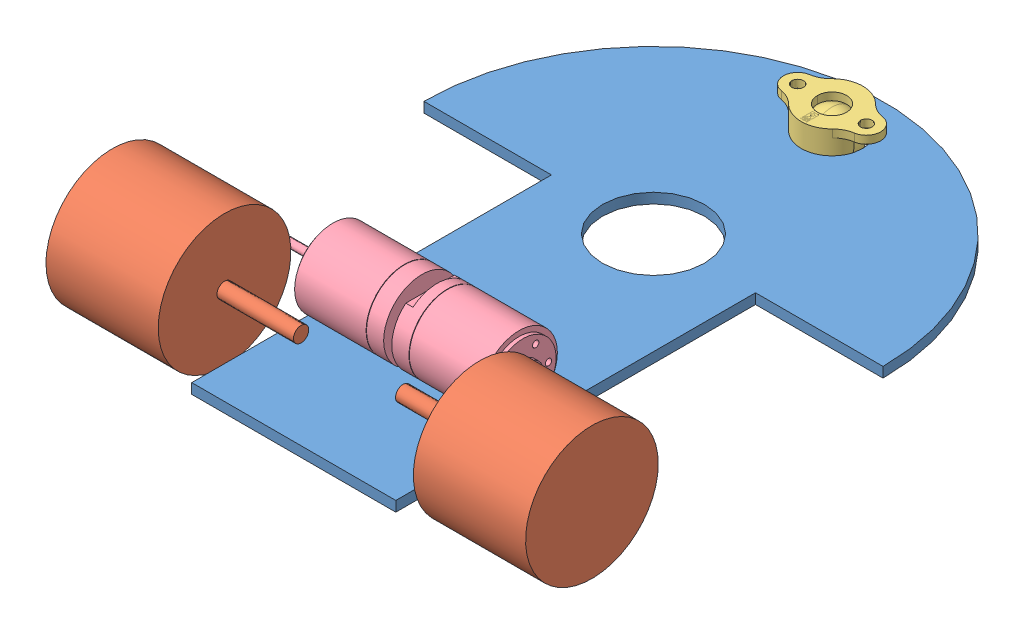
SolidWorks assembly Robot, configuration Défaut. Lengths in mm.
Overall size (94 27.84 117.98).
6 component instances, 4 part files, 13 mates.
Components (placement in the parent):
- PCB-1: PCB [Défaut] at (2.6234 1.4777 105.5) size (90 2 115.5)
- Roue-3: Roue [Défaut] at (22.6234 10.9777 124.0626) x (0 -0.073602 -0.997288) z (1 0 0) size (26 26 37)
- pololu-ball-caster-with-0-375in-ball.step-1: pololu-ball-caster-with-0-375in-ball.step [Défaut] at (-2.3766 6.5227 30) x (-1 0 0) z (0 -1 0) size (19.05 12.07 10.07)
- Moteur+encodeur.stp-2: Moteur+encodeur.stp [Défaut] at (0.8234 10.9777 109.585) x (0 0 1) z (1 0 0) size (15 15 26.3)
- Moteur+encodeur.stp-4: Moteur+encodeur.stp [Défaut] at (-5.5766 10.9777 109.585) x (0 0 1) z (-1 0 0) size (15 15 26.3)
- Roue-11: Roue [Défaut] at (-27.3766 10.9777 124.0626) x (0 0.073602 0.997288) z (-1 0 0) size (26 26 37)
Mates (geometry in assembly coordinates):
- Distance2: distance = 5 mm anti-aligned: plane of Roue-2 through (22.6234 10.9777 80.5) normal (-1 0 0); plane of PCB-1 through (17.6234 3.4777 105.5) normal (1 0 0)
- Distance6: distance = 7.5 mm: plane of PCB-1 through (2.6234 3.4777 105.5) normal (0 1 0); cylinder of Roue-2 through (7.6234 10.9777 80.5) axis (1 0 0) radius 1.5
- Distance3: distance = 2.5 mm anti-aligned: cylinder of Roue-2 through (44.6234 10.9777 80.5) axis (-1 0 0) radius 13; plane of PCB-1 through (2.6234 3.4777 65) normal (0 0 1)
- Distance4: distance = 5 mm anti-aligned: plane of Roue-3 through (22.6234 10.9777 124.0626) normal (-1 0 0); plane of PCB-1 through (17.6234 3.4777 105.5) normal (1 0 0)
- Distance7: distance = 7.5 mm: plane of PCB-1 through (2.6234 3.4777 105.5) normal (0 1 0); cylinder of Roue-3 through (7.6234 10.9777 124.0626) axis (1 0 0) radius 1.5
- Distance5: distance = 2.5 mm: cylinder of Roue-3 through (44.6234 10.9777 124.0626) axis (-1 0 0) radius 13; cylinder of Roue-2 through (44.6234 10.9777 80.5) axis (-1 0 0) radius 13
- Coaxiale1: concentric aligned: cylinder of PCB-1 through (-2.3766 11.4777 30) axis (0 -1 0) radius 6.03; cylinder of pololu-ball-caster-with-0-375in-ball.step-1 through (-2.3766 8.0467 30) axis (0 -1 0) radius 6.0325
- Distance9: distance = 3.5 mm: point of pololu-ball-caster-with-0-375in-ball.step-1; plane of PCB-1 through (2.6234 1.4777 105.5) normal (0 -1 0)
- Parallèle5: parallel aligned: line of PCB-1 through (-22.3766 3.4777 65) axis (0 0 1); line of pololu-ball-caster-with-0-375in-ball.step-1 through (-3.0052 8.0467 33.2059) axis (0 0 1)
- Tangent1: tangent anti-aligned: plane of PCB-1 through (2.6234 3.4777 105.5) normal (0 1 0); cylinder of 1516T_SR.stp-2 through (0.8234 10.9777 109.585) axis (1 0 0) radius 7.5
- Distance11: distance = 0 mm aligned: plane of 1516T_SR.stp-2 through (17.6234 9.2277 109.585) normal (1 0 0); plane of PCB-1 through (17.6234 3.4777 105.5) normal (1 0 0)
- Parallèle7: parallel aligned: plane of PCB-1 through (2.6234 3.4777 105.5) normal (0 1 0); plane of 1516T_SR.stp-2 through (-1.5766 16.7777 114.34) normal (0 1 0)
- Distance12: distance = 14.25 mm: cylinder of Moteur+encodeur.stp-2 through (0.8234 10.9777 109.585) axis (1 0 0) radius 7.5; cylinder of Roue-2 through (7.6234 10.9777 80.5) axis (1 0 0) radius 1.5
